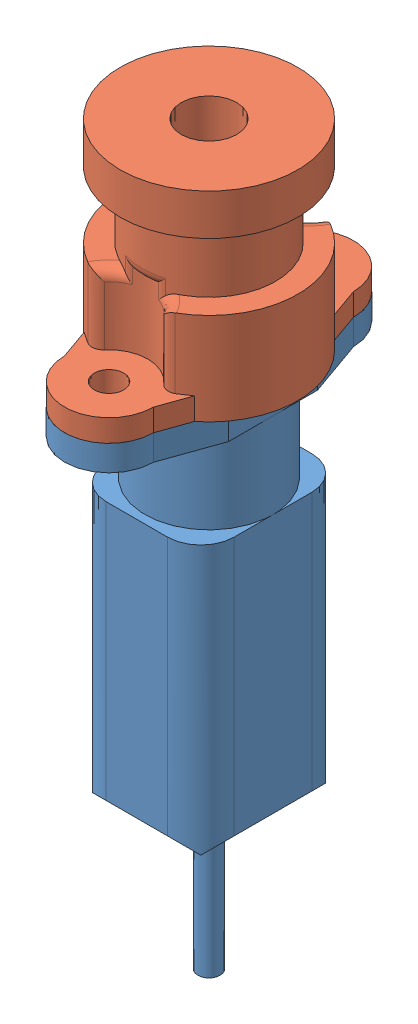
SolidWorks assembly Assem6, configuration Default. Lengths in mm.
Overall size (16 66.3 26).
2 component instances, 2 part files, 6 mates.
Components (placement in the parent):
- BLTouch-1: BLTouch [Default] at (-15 -18 71.7) x (0 0 1) z (-1 0 0) size (26 48.3 11.53)
- BLTouchAdapter_2nd_Hotend_Adapter-1: BLTouchAdapter_2nd_Hotend_Adapter [Default] at (0 -18 0) x (1 0 0) z (0 1 0) size (16 26 18)
Mates (geometry in assembly coordinates):
- Coincident3: coincident: plane of BLTouchAdapter_2nd_Hotend_Adapter-1 through (0 0 0) normal (0 1 0); plane of assembly through (0 0 0) normal (0 1 0)
- Coincident4: coincident: plane of BLTouchAdapter_2nd_Hotend_Adapter-1; plane of assembly through (0 0 0) normal (1 0 0)
- Coincident6: coincident anti-aligned: plane of BLTouchAdapter_2nd_Hotend_Adapter-1 through (0 -18 0) normal (0 0 -1); plane of assembly
- Concentric1: concentric: cylinder of BLTouch-1 through (0 -18 0) axis (0 -1 0) radius 1.6; cylinder of BLTouchAdapter_2nd_Hotend_Adapter-1 through (0 7.0711 0) axis (0 -1 0) radius 2.5
- Coincident7: coincident: plane of BLTouch-1 through (0 -18 9) normal (0 1 0); plane of BLTouchAdapter_2nd_Hotend_Adapter-1 through (0 -18 0) normal (0 -1 0)
- Concentric2: concentric aligned: cylinder of BLTouch-1 through (0 -18 9) axis (0 -1 0) radius 1.6; cylinder of BLTouchAdapter_2nd_Hotend_Adapter-1 through (0 -16 9) axis (0 -1 0) radius 1.325
